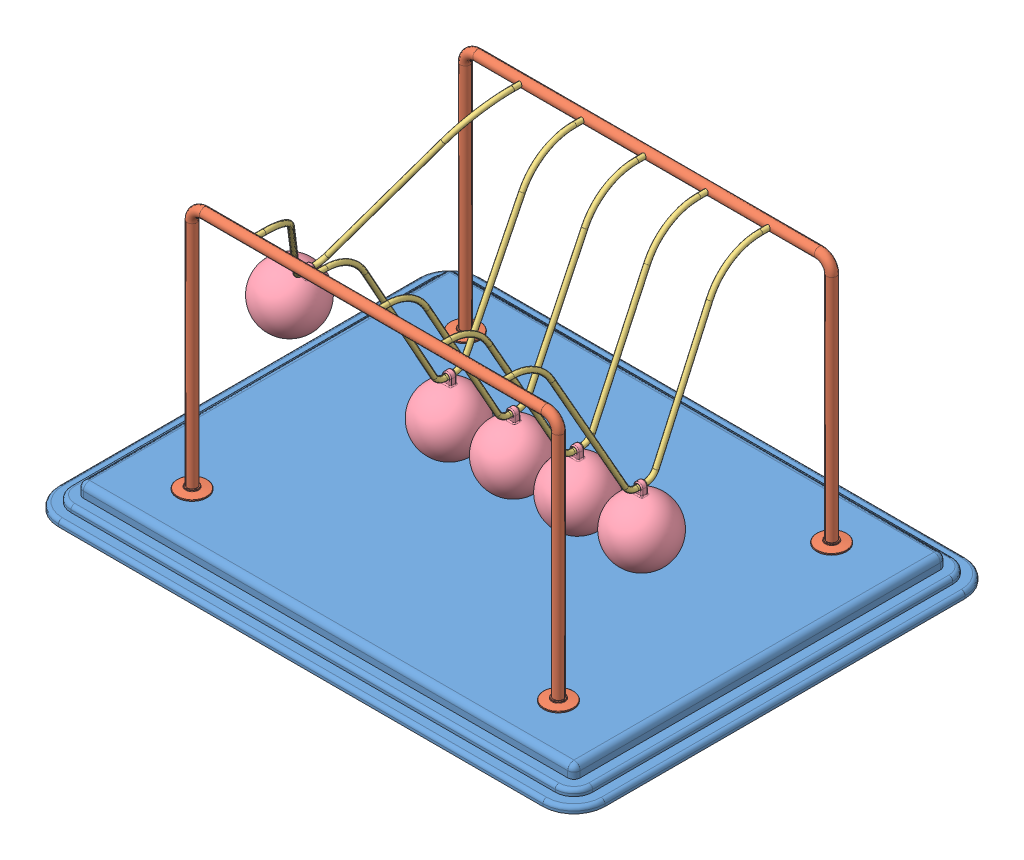
SolidWorks assembly Newtons Cradle NewtonsCradle 0240, configuration Default. Lengths in mm.
Overall size (440 222 340).
13 component instances, 4 part files, 34 mates.
Components (placement in the parent):
- Base NewtonsCradle 0240-1: Base NewtonsCradle 0240 [Default] at (-16.2968 -4.1587 11.425) size (440 20 340)
- frame NewtonsCradle 0240-1: frame NewtonsCradle 0240 [Default] at (-16.2968 144.4547 -98.575) size (319 202 24)
- frame NewtonsCradle 0240-2: frame NewtonsCradle 0240 [Default] at (-16.2968 144.4547 121.425) x (-1 0 0) z (0 0 -1) size (319 202 24)
- Hanging thing NewtonsCradle 0240-1: Hanging thing NewtonsCradle 0240 [Default] at (-157.6326 134.1825 11.425) x (0 0 1) z (-0.859985 0.510319 0) size (220 129 4)
- Hanging thing NewtonsCradle 0240-2: Hanging thing NewtonsCradle 0240 [Default] at (-66.576 122.8418 11.425) x (0 0 1) z (-0.999994 0.003446 0) size (220 129 4)
- Hanging thing NewtonsCradle 0240-3: Hanging thing NewtonsCradle 0240 [Default] at (-15.6923 122.8436 11.425) x (0 0 1) z (-0.999972 -0.007464 0) size (220 129 4)
- Hanging thing NewtonsCradle 0240-4: Hanging thing NewtonsCradle 0240 [Default] at (35.2213 122.8555 11.425) x (0 0 1) z (-0.999824 -0.018742 0) size (220 129 4)
- Hanging thing NewtonsCradle 0240-5: Hanging thing NewtonsCradle 0240 [Default] at (86.0287 122.8747 11.425) x (0 0 1) z (-0.999588 -0.028711 0) size (220 129 4)
- Sphere NewtonsCradle 0240-1: Sphere NewtonsCradle 0240 [Default] at (-195.3962 70.5436 11.425) x (0.859985 -0.510319 0) z (0 0 1) size (50 58.5 50)
- Sphere NewtonsCradle 0240-2: Sphere NewtonsCradle 0240 [Default] at (88.1533 48.9052 11.425) x (0.999588 0.028711 0) z (0 0 1) size (50 58.5 50)
- Sphere NewtonsCradle 0240-3: Sphere NewtonsCradle 0240 [Default] at (-15.14 48.8456 11.425) x (0.999972 0.007464 0) z (0 0 1) size (50 58.5 50)
- Sphere NewtonsCradle 0240-4: Sphere NewtonsCradle 0240 [Default] at (36.6081 48.8685 11.425) x (0.999824 0.018742 0) z (0 0 1) size (50 58.5 50)
- Sphere NewtonsCradle 0240-5: Sphere NewtonsCradle 0240 [Default] at (-66.831 48.8422 11.425) x (0.999994 -0.003446 0) z (0 0 1) size (50 58.5 50)
Mates (geometry in assembly coordinates):
- Coincident1: coincident anti-aligned: plane of Base-1 through (-211.2968 5.8413 156.425) normal (0 1 0); plane of frame-2 through (-175.7968 5.8413 121.425) normal (0 -1 0)
- Coincident2: coincident anti-aligned: plane of Base-1 through (-211.2968 5.8413 156.425) normal (0 1 0); plane of frame-1 through (143.2032 5.8413 -98.575) normal (0 -1 0)
- Concentric1: concentric anti-aligned: cylinder of frame-1 through (-116.2968 203.8413 -94.575) axis (0 0 -1) radius 2; cylinder of frame-2 through (-116.2968 203.8413 117.425) axis (0 0 1) radius 2
- Concentric2: concentric anti-aligned: cylinder of frame-1 through (83.7032 203.8413 -94.575) axis (0 0 -1) radius 2; cylinder of frame-2 through (83.7032 203.8413 117.425) axis (0 0 1) radius 2
- Distance1: distance = 60 mm: plane of frame-1 through (-16.2968 144.4547 -98.575) normal (0 0 1); line of Base-1 through (-211.2968 -12.1587 -158.575) axis (1 0 0)
- Distance2: distance = 60 mm: line of Base-1 through (178.7032 -12.1587 181.425) axis (-1 0 0); plane of frame-2 through (-16.2968 144.4547 121.425) normal (0 0 -1)
- Distance3: distance = 220 mm: plane of frame-2 through (-16.2968 144.4547 121.425) normal (-1 0 0); line of Base-1 through (-236.2968 -12.1587 156.425) axis (0 0 -1)
- Concentric3: concentric anti-aligned: cylinder of frame-1 through (-116.2968 203.8413 -94.575) axis (0 0 -1) radius 2; cylinder of Hanging thing-1 through (-116.2968 203.8413 111.425) axis (0 0 1) radius 2
- Concentric4: concentric anti-aligned: cylinder of frame-1 through (-116.2968 203.8413 -94.575) axis (0 0 -1) radius 2; cylinder of Hanging thing-1 through (-116.2968 203.8413 -98.575) axis (0 0 1) radius 2
- Concentric5: concentric aligned: cylinder of frame-2 through (-66.2968 203.8413 117.425) axis (0 0 1) radius 2; cylinder of Hanging thing-2 through (-66.2968 203.8413 111.425) axis (0 0 1) radius 2
- Concentric6: concentric aligned: cylinder of frame-2 through (-16.2968 203.8413 117.425) axis (0 0 1) radius 2; cylinder of Hanging thing-3 through (-16.2968 203.8413 111.425) axis (0 0 1) radius 2
- Concentric7: concentric aligned: cylinder of frame-2 through (33.7032 203.8413 117.425) axis (0 0 1) radius 2; cylinder of Hanging thing-4 through (33.7032 203.8413 111.425) axis (0 0 1) radius 2
- Concentric8: concentric aligned: cylinder of frame-2 through (83.7032 203.8413 117.425) axis (0 0 1) radius 2; cylinder of Hanging thing-5 through (83.7032 203.8413 111.425) axis (0 0 1) radius 2
- Coincident5: coincident anti-aligned: plane of frame-2 through (83.7032 203.8413 121.425) normal (0 0 -1); plane of Hanging thing-5 through (83.7032 203.8413 121.425) normal (0 0 1)
- Coincident6: coincident anti-aligned: plane of frame-2 through (33.7032 203.8413 121.425) normal (0 0 -1); plane of Hanging thing-4 through (33.7032 203.8413 121.425) normal (0 0 1)
- Coincident7: coincident anti-aligned: plane of frame-2 through (-16.2968 203.8413 121.425) normal (0 0 -1); plane of Hanging thing-3 through (-16.2968 203.8413 121.425) normal (0 0 1)
- Coincident8: coincident anti-aligned: plane of frame-2 through (-66.2968 203.8413 121.425) normal (0 0 -1); plane of Hanging thing-2 through (-66.2968 203.8413 121.425) normal (0 0 1)
- Coincident9: coincident anti-aligned: plane of frame-2 through (-116.2968 203.8413 121.425) normal (0 0 -1); plane of Hanging thing-1 through (-116.2968 203.8413 121.425) normal (0 0 1)
- Concentric9: concentric anti-aligned: cylinder of Hanging thing-1 through (-117.0163 78.8434 7.925) axis (0 0 1) radius 2; cylinder of Sphere-1 through (-117.0163 78.8434 13.925) axis (0 0 -1) radius 2
- Concentric13: concentric anti-aligned: cylinder of Hanging thing-2 through (-66.7276 78.842 7.925) axis (0 0 1) radius 2; cylinder of Sphere-5 through (-66.7276 78.842 13.925) axis (0 0 -1) radius 2
- Concentric15: concentric anti-aligned: cylinder of Hanging thing-3 through (-15.3639 78.8448 7.925) axis (0 0 1) radius 2; cylinder of Sphere-3 through (-15.3639 78.8448 13.925) axis (0 0 -1) radius 2
- Concentric16: concentric anti-aligned: cylinder of Hanging thing-5 through (87.292 78.8928 7.925) axis (0 0 1) radius 2; cylinder of Sphere-2 through (87.292 78.8928 13.925) axis (0 0 -1) radius 2
- Concentric17: concentric anti-aligned: cylinder of Hanging thing-4 through (36.0459 78.8632 7.925) axis (0 0 1) radius 2; cylinder of Sphere-4 through (36.0459 78.8632 13.925) axis (0 0 -1) radius 2
- Parallel1: parallel anti-aligned: plane of Hanging thing-1; plane of Sphere-1
- Coincident22: coincident anti-aligned: plane of Hanging thing-1; plane of Sphere-1
- Coincident12: coincident aligned: plane of Hanging thing-2 through (-66.576 122.8418 11.425) normal (0 0 1); plane of Sphere-5 through (-66.831 48.8422 11.425) normal (0 0 1)
- Coincident10: coincident aligned: plane of Hanging thing-1 through (-116.763 122.8426 11.425) normal (0 0 1); plane of Sphere-1 through (-118.5806 48.8842 11.425) normal (0 0 1)
- Coincident13: coincident anti-aligned: plane of Hanging thing-2 through (-66.576 122.8418 11.425) normal (-0.999994 0.003446 0); plane of Sphere-5 through (-66.831 48.8422 11.425) normal (0.999994 -0.003446 0)
- Coincident14: coincident anti-aligned: plane of Hanging thing-3 through (-15.6923 122.8436 11.425) normal (-0.999972 -0.007464 0); plane of Sphere-3 through (-15.14 48.8456 11.425) normal (0.999972 0.007464 0)
- Coincident15: coincident aligned: plane of Hanging thing-3 through (-15.6923 122.8436 11.425) normal (0 0 1); plane of Sphere-3 through (-15.14 48.8456 11.425) normal (0 0 1)
- Coincident18: coincident aligned: plane of Hanging thing-4 through (35.2213 122.8555 11.425) normal (0 0 1); plane of Sphere-4 through (36.6081 48.8685 11.425) normal (0 0 1)
- Coincident19: coincident anti-aligned: plane of Hanging thing-4 through (35.2213 122.8555 11.425) normal (-0.999824 -0.018742 0); plane of Sphere-4 through (36.6081 48.8685 11.425) normal (0.999824 0.018742 0)
- Coincident20: coincident anti-aligned: plane of Hanging thing-5 through (86.0287 122.8747 11.425) normal (-0.999588 -0.028711 0); plane of Sphere-2 through (88.1533 48.9052 11.425) normal (0.999588 0.028711 0)
- Coincident21: coincident aligned: plane of Hanging thing-5 through (86.0287 122.8747 11.425) normal (0 0 1); plane of Sphere-2 through (88.1533 48.9052 11.425) normal (0 0 1)
